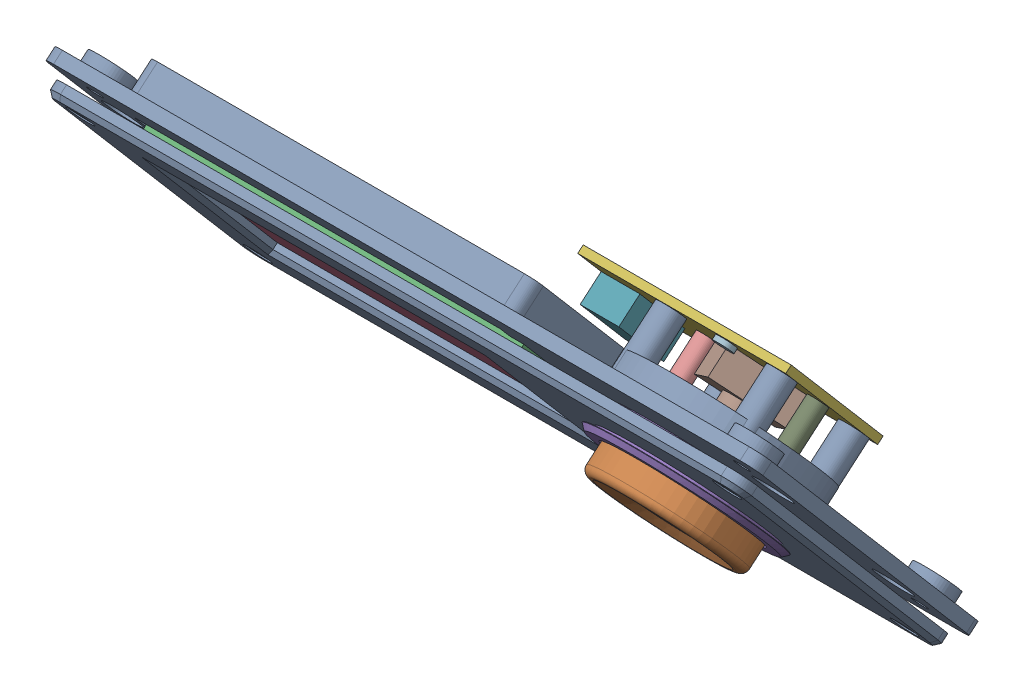
SolidWorks assembly Control Panel_1.step, configuration Default. Lengths in mm.
Overall size (154.8 68.54 62.85).
12 component instances, 6 part files, 0 mates.
Components (placement in the parent):
- Control Panel Cover.step-1: Control Panel Cover.step [Default] at (0 0 10) size (151.2 55.15 47.7)
  - Control Panel Cover_1.step-1: Control Panel Cover_1.step [Default] at (-36.6 136.5283 30.1117) x (1 0 0) z (0 -0.649781 0.760121) size (151.2 70.2 2.75)
- Knob.step-1: Knob.step [Default] at (0 -125 0) size (29.7 28.03 25.68)
  - Knob_1.step-1: Knob_1.step [Default] at (5.9 255.0604 47.7549) x (1 0 0) z (0 0.649781 -0.760121) size (29.7 29.7 8.4)
- LCD and UI Ctrl.step-1: LCD and UI Ctrl.step [Default] at (-150 0 0) size (83.6 40.13 36.15)
  - LCD and UI Ctrl_1.step-1: LCD and UI Ctrl_1.step [Default] at (90.55 138.1527 38.2114) x (1 0 0) z (0 -0.649781 0.760121) size (83.6 45.1 9)
- Knob Light Pipe.step-1: Knob Light Pipe.step [Default] at (0 -80 0) x (1 0 0) z (0 0 -1) size (37.8 36.98 34.22)
  - Knob Light Pipe_1.step-1: Knob Light Pipe_1.step [Default] at (5.9 -213.6991 -43.4982) x (1 0 0) z (0 -0.649781 0.760121) size (37.8 37.8 12.7)
- Encoder.step-1: Encoder.step [Default] at (130 0 0) size (45.1 40.56 40.1)
  - Encoder_1.step-1: Encoder_1.step [Default] at (-131.65 149.5278 24.9817) x (1 0 0) z (0 -0.649781 0.760121) size (45.1 30.65 26.56)
- Control Panel Back Frame.step-1: Control Panel Back Frame.step [Default] x (1 0 0) z (0 0 -1) size (154.8 67.09 60.79)
  - Control Panel Back Frame_1.step-1: Control Panel Back Frame_1.step [Default] at (-36.6 -137.5978 -38.9375) x (1 0 0) z (0 -0.649781 0.760121) size (154.8 73.9 16.8)
